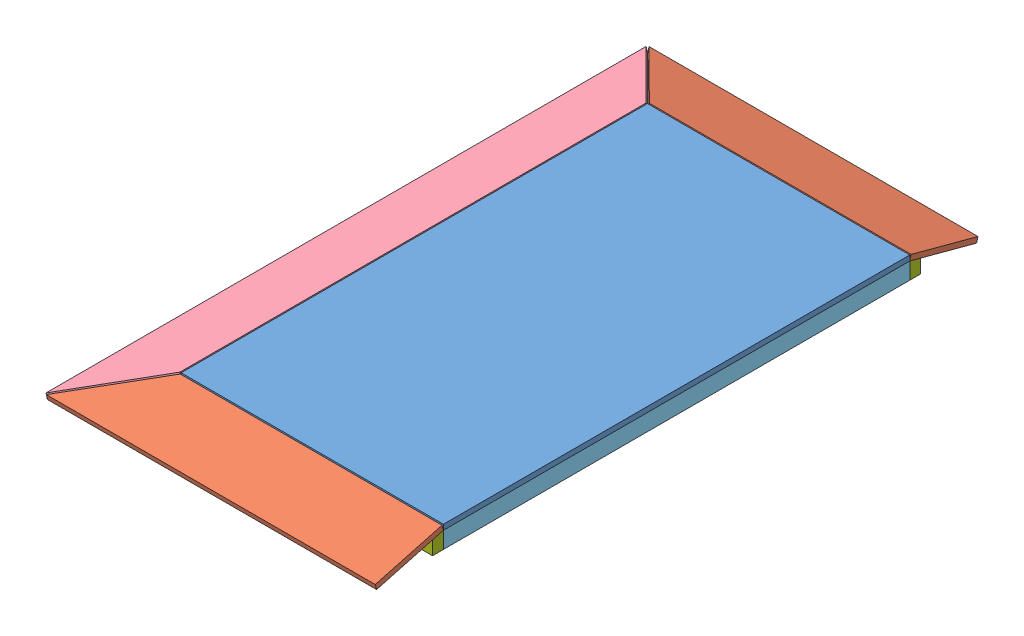
SolidWorks assembly TE-19105, configuration Default. Lengths in mm.
Overall size (1152.2 80.71 2101.21).
13 component instances, 7 part files, 37 mates.
Components (placement in the parent):
- TE-19105-01-1: TE-19105-01 [Default] at (1369.9395 472.555 2657.2844) x (0 0 -1) z (0 -1 0) size (1625.6 914.4 18.26)
- TE-19105-02-1: TE-19105-02 [Default] at (1327.6034 412.6467 3555.6637) x (-1 0 0) z (0 -0.965926 -0.258819) size (1146.56 241.3 18.26)
- TE-19105-05-12: TE-19105-05 [Default] at (1810.6684 405.1511 3315.894) x (0 0 1) z (-1 0 0) size (38.1 57.94 838.2)
- TE-19105-05-13: TE-19105-05 [Default] at (972.4684 405.1511 2240.6811) x (0 0 -1) z (1 0 0) size (38.1 57.94 838.2)
- TE-19105-05-14: TE-19105-05 [Default] at (972.4684 405.1511 2782.5478) x (0 0 -1) z (1 0 0) size (38.1 57.94 838.2)
- TE-19105-05-18: TE-19105-05 [Default] at (972.4684 405.1511 1717.8644) x (0 0 -1) z (1 0 0) size (38.1 57.94 838.2)
- TE-19105-03-1: TE-19105-03 [Default] at (403.0357 311.9286 2336.0752) x (0 0 1) z (-0.258819 0.965926 0) size (2091.92 241.3 18.26)
- TE-19105-06-1: TE-19105-06 [Default] at (943.0635 419.3158 1704.0792) size (38.1 57.94 1625.6)
- TE-19105-06-2: TE-19105-06 [Default] at (1819.3635 419.3158 1704.0792) size (38.1 57.94 1625.6)
- TE-19105-02-2: TE-19105-02 [Default] at (1327.6034 395.0125 1482.8198) x (-1 0 0) z (0 0.965926 -0.258819) size (1146.56 241.3 18.26)
- TE-19105-04-1: TE-19105-04 [Default] at (911.6078 426.8655 3278.8792) x (-1 0 0) z (0 0 -1) size (38.1 57.94 1524)
- TE-19105-07-1: TE-19105-07 [Default] at (934.3684 419.0092 1688.9965) x (0 0 -1) z (1 0 0) size (38.1 57.94 914.4)
- TE-19105-07-2: TE-19105-07 [Default] at (1848.7684 419.0092 3344.7619) x (0 0 1) z (-1 0 0) size (38.1 57.94 914.4)
Mates (geometry in assembly coordinates):
- Coincident78: coincident: plane of TE-19105-01-1 through (1369.9395 454.2988 2657.2844) normal (0 -1 0); plane of TE-19105-05-12 through (972.4684 454.2988 3291.5792) normal (0 1 0)
- Coincident81: coincident: plane of TE-19105-01-1 through (1369.9395 454.2988 2657.2844) normal (0 -1 0); plane of TE-19105-05-18 through (1810.6684 454.2988 1742.1792) normal (0 1 0)
- Coincident90: coincident: plane of TE-19105-01-1 through (1369.9395 454.2988 2657.2844) normal (0 -1 0); plane of TE-19105-05-14 through (1810.6684 454.2988 2806.8625) normal (0 1 0)
- Coincident93: coincident: plane of TE-19105-01-1 through (1369.9395 454.2988 2657.2844) normal (0 -1 0); plane of TE-19105-05-13 through (1810.6684 454.2988 2264.9959) normal (0 1 0)
- Parallel8: parallel: plane of TE-19105-01-1 through (1369.9395 472.555 2657.2844) normal (0 1 0); plane of assembly through (0 0 0) normal (0 1 0)
- Coincident129: coincident: plane of TE-19105-01-1 through (1369.9395 454.2988 2657.2844) normal (0 -1 0); plane of TE-19105-06-1 through (934.3684 454.2988 3329.6792) normal (0 1 0)
- Coincident130: coincident: plane of assembly; plane of assembly; plane of TE-19105-05-12 through (972.4684 405.1511 3315.894) normal (-1 0 0); plane of TE-19105-06-1 through (972.4684 454.2988 3329.6792) normal (1 0 0)
- Coincident132: coincident: plane of TE-19105-01-1 through (1369.9395 454.2988 2657.2844) normal (0 -1 0); plane of TE-19105-06-2 through (1810.6684 454.2988 3329.6792) normal (0 1 0)
- Coincident133: coincident: plane of assembly; plane of assembly; plane of TE-19105-05-14 through (1810.6684 405.1511 2782.5478) normal (1 0 0); plane of TE-19105-06-2 through (1810.6684 454.2988 3329.6792) normal (-1 0 0)
- Distance5: distance = 484.7167 mm: plane of assembly; plane of assembly; plane of TE-19105-05-12 through (972.4684 454.2988 3291.5792) normal (0 0 -1); plane of TE-19105-05-14 through (1810.6684 454.2988 2806.8625) normal (0 0 1)
- Distance6: distance = 503.7667 mm: plane of assembly; plane of assembly; plane of TE-19105-05-14 through (1810.6684 454.2988 2768.7625) normal (0 0 -1); plane of TE-19105-05-13 through (1810.6684 454.2988 2264.9959) normal (0 0 1)
- Distance7: distance = 484.7167 mm: plane of assembly; plane of assembly; plane of TE-19105-05-13 through (1810.6684 454.2988 2226.8959) normal (0 0 -1); plane of TE-19105-05-18 through (1810.6684 454.2988 1742.1792) normal (0 0 1)
- Coincident138: coincident: plane of assembly; plane of assembly; plane of TE-19105-05-14 through (972.4684 405.1511 2782.5478) normal (-1 0 0); plane of TE-19105-06-1 through (972.4684 454.2988 3329.6792) normal (1 0 0)
- Coincident139: coincident: plane of assembly; plane of assembly; plane of TE-19105-05-13 through (1810.6684 405.1511 2240.6811) normal (1 0 0); plane of TE-19105-06-2 through (1810.6684 454.2988 3329.6792) normal (-1 0 0)
- Coincident140: coincident: plane of assembly; plane of assembly; plane of TE-19105-05-18 through (1810.6684 405.1511 1717.8644) normal (1 0 0); plane of TE-19105-06-2 through (1810.6684 454.2988 3329.6792) normal (-1 0 0)
- Coincident141: coincident: plane of TE-19105-01-1 through (1848.7684 454.2988 3329.6792) normal (1 0 0); plane of TE-19105-06-2 through (1848.7684 454.2988 3329.6792) normal (1 0 0)
- Coincident142: coincident: plane of TE-19105-01-1 through (1848.7684 454.2988 1704.0792) normal (0 0 -1); plane of TE-19105-05-18 through (1810.6684 454.2988 1704.0792) normal (0 0 -1)
- Coincident150: coincident: plane of assembly; plane of assembly; plane of TE-19105-05-12 through (972.4684 454.2988 3329.6792) normal (0 0 1); plane of TE-19105-06-1 through (943.0635 419.3158 3329.6792) normal (0 0 1)
- Coincident151: coincident: plane of assembly; plane of assembly; plane of TE-19105-05-12 through (972.4684 454.2988 3329.6792) normal (0 0 1); plane of TE-19105-06-2 through (1819.3635 419.3158 3329.6792) normal (0 0 1)
- Coincident152: coincident: plane of assembly; plane of assembly; plane of TE-19105-05-12 through (972.4684 454.2988 3329.6792) normal (0 0 1); plane of TE-19105-07-2 through (934.3684 454.2988 3329.6792) normal (0 0 -1)
- Coincident153: coincident: plane of assembly; plane of assembly; plane of TE-19105-06-2 through (1848.7684 454.2988 3329.6792) normal (1 0 0); plane of TE-19105-07-2 through (1848.7684 419.0092 3344.7619) normal (1 0 0)
- Coincident154: coincident: plane of assembly; plane of assembly; plane of TE-19105-05-12 through (972.4684 396.355 3291.5792) normal (0 -1 0); plane of TE-19105-07-2 through (934.3684 396.355 3329.6792) normal (0 -1 0)
- Coincident155: coincident: plane of assembly; plane of assembly; plane of TE-19105-05-18 through (1810.6684 454.2988 1704.0792) normal (0 0 -1); plane of TE-19105-07-1 through (1848.7684 454.2988 1704.0792) normal (0 0 1)
- Coincident156: coincident: plane of assembly; plane of assembly; plane of TE-19105-06-2 through (1848.7684 454.2988 3329.6792) normal (1 0 0); plane of TE-19105-07-1 through (1848.7684 419.0092 1688.9965) normal (1 0 0)
- Coincident157: coincident: plane of assembly; plane of assembly; plane of TE-19105-05-18 through (1810.6684 396.355 1742.1792) normal (0 -1 0); plane of TE-19105-07-1 through (1848.7684 396.355 1704.0792) normal (0 -1 0)
- Coincident158: coincident: plane of assembly; plane of assembly; plane of TE-19105-02-2 through (1327.6034 395.0125 1482.8198) normal (0 -0.965926 0.258819); plane of TE-19105-07-1 through (1848.7684 454.2988 1704.0792) normal (0 0.965926 -0.258819)
- Coincident159: coincident: plane of assembly; plane of assembly; plane of TE-19105-02-2 through (1848.7684 471.933 1699.3541) normal (1 0 0); plane of TE-19105-07-1 through (1848.7684 419.0092 1688.9965) normal (1 0 0)
- Coincident160: coincident: line of TE-19105-01-1 through (934.3684 454.2988 1704.0792) axis (1 0 0); line of TE-19105-02-2 through (936.0484 454.2988 1704.0792) axis (1 0 0)
- Coincident161: coincident: plane of assembly; plane of assembly; plane of TE-19105-06-1 through (934.3684 454.2988 3329.6792) normal (-1 0 0); plane of TE-19105-04-1 through (934.3684 454.2988 1754.8792) normal (1 0 0)
- Coincident162: coincident: plane of assembly; plane of assembly; plane of TE-19105-06-1 through (934.3684 396.355 3329.6792) normal (0 -1 0); plane of TE-19105-04-1 through (934.3684 396.355 1754.8792) normal (0 -1 0)
- Distance10: distance = 50.8 mm: plane of TE-19105-04-1 through (911.6078 426.8655 3278.8792) normal (0 0 1); plane of TE-19105-01-1 through (1848.7684 454.2988 3329.6792) normal (0 0 1)
- Coincident168: coincident: line of assembly; line of assembly; line of TE-19105-02-1 through (936.0484 454.2988 3329.6792) axis (1 0 0); line of TE-19105-07-2 through (934.3684 454.2988 3329.6792) axis (1 0 0)
- Coincident169: coincident: plane of assembly; plane of assembly; plane of TE-19105-02-1 through (1848.7684 454.2988 3329.6792) normal (1 0 0); plane of TE-19105-06-2 through (1848.7684 454.2988 3329.6792) normal (1 0 0)
- Coincident170: coincident: line of assembly; line of assembly; line of TE-19105-03-1 through (934.3684 454.2988 3329.0442) axis (0 0 -1); line of TE-19105-04-1 through (934.3684 454.2988 1754.8792) axis (0 0 1)
- Coincident171: coincident: plane of assembly; plane of assembly; plane of TE-19105-02-1 through (1327.6034 395.0125 3550.9387) normal (0 -0.965926 -0.258819); plane of TE-19105-07-2 through (934.3684 454.2988 3329.6792) normal (0 0.965926 0.258819)
- Coincident172: coincident: plane of assembly; plane of assembly; plane of TE-19105-03-1 through (403.0357 311.9286 2336.0752) normal (0.258819 -0.965926 0); plane of TE-19105-04-1 through (934.3684 454.2988 1754.8792) normal (-0.258819 0.965926 0)
- Distance11: distance = 0.635 mm: plane of TE-19105-01-1 through (1848.7684 454.2988 3329.6792) normal (0 0 1); line of TE-19105-03-1 through (929.6434 471.933 3329.0442) axis (0.258819 -0.965926 0)
